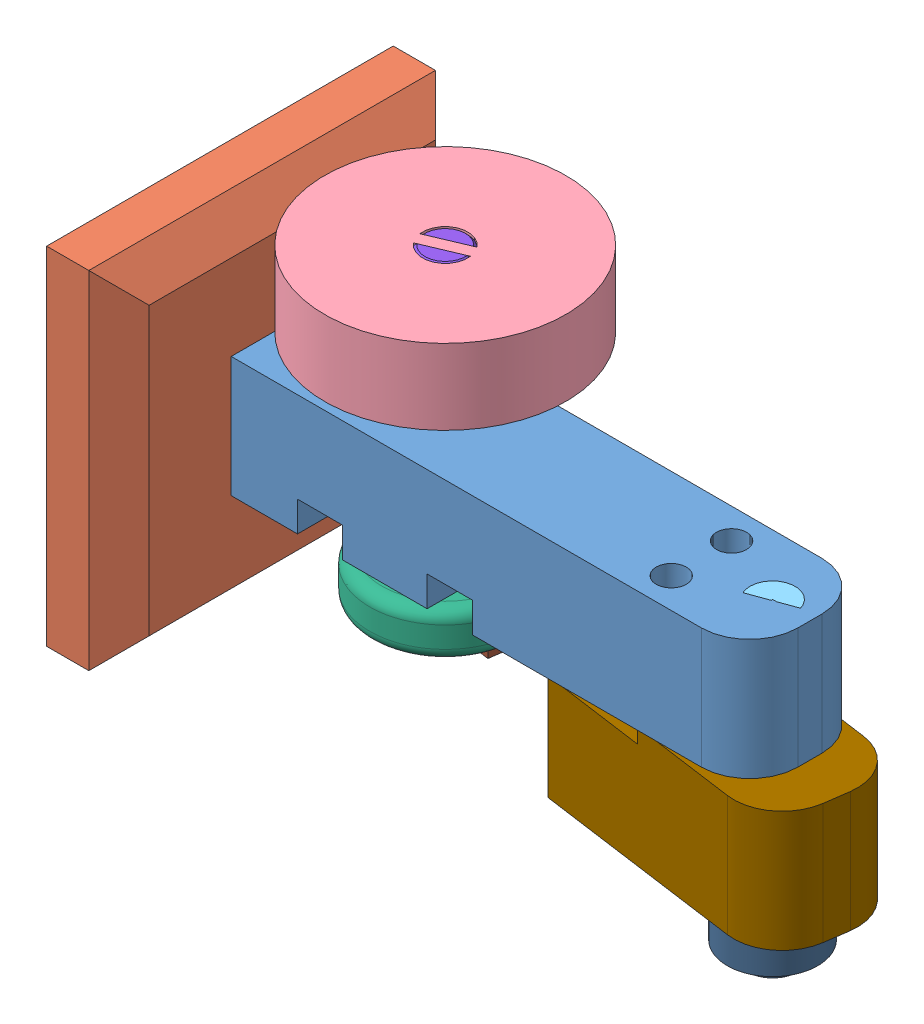
SolidWorks assembly Assem1 final project, configuration Default. Lengths in mm.
Overall size (134.06 95.45 73.03).
11 component instances, 11 part files, 22 mates.
Components (placement in the parent):
- PART7 main body-1: PART7 main body [Default] at (-9.211 -41.619 -75.801) x (0 0 -1) z (1 0 0) size (25.4 25.4 109.22)
- PART1base-1: PART1base [Default] at (-133.671 -41.0985 -75.9637) x (0 0 1) z (-1 0 0) size (73.03 73.03 15.24)
- PART11 bolt-1: PART11 bolt [Default] at (-124.146 -41.0985 -75.9637) x (0 0 -1) z (1 0 0) size (9.53 9.53 19.05)
- PART10 flywheel-1: PART10 flywheel [Default] at (-86.046 1.2562 -75.801) x (-0.388119 0 -0.921609) z (0 -1 0) size (50.8 50.8 25.4)
- PART2CONNECTING BOLT-1: PART2CONNECTING BOLT [Default] at (-17.085 -28.919 -75.801) x (0.999969 0 0.007855) z (0 1 0) size (9.53 9.53 57.15)
- PART3 SHAFT WHEEL-1: PART3 SHAFT WHEEL [Default] at (-86.046 -63.844 -75.801) x (0.990415 0 0.138122) z (0 1 0) size (32.12 31.75 9.9)
- PART4 SMALL BAR-1: PART4 SMALL BAR [Default] at (-84.7304 -54.319 -85.2347) x (0.683793 0 -0.729676) z (0 -1 0) size (4.75 4.75 19.05)
- PART5 BIG BAR-1: PART5 BIG BAR [Default] at (-86.046 1.2562 -75.801) x (-0.388119 0 -0.921609) z (0 1 0) size (9.53 9.53 65.1)
- PART6 cylinder-1: PART6 cylinder [Default] at (-1.3622 -68.797 -73.6084) x (0.138122 0 -0.990415) z (0.990415 0 0.138122) size (25.4 25.4 54.61)
- PART8 holder-1: PART8 holder [Default] at (-17.085 -87.4074 -75.801) x (0.756947 0 -0.653476) z (-0.653476 0 -0.756947) size (19.05 12.7 19.05)
- PART9 piston-1: PART9 piston [Default] at (-55.8004 -68.797 -81.2002) x (0 -1 0) z (-0.990415 0 -0.138122) size (12.7 12.7 46.61)
Mates (geometry in assembly coordinates):
- Coincident4: coincident: plane of assembly; plane of assembly; plane of PART7 main body-1 through (-118.431 -41.619 -75.801) normal (-1 0 0); plane of PART1base-1 through (-118.431 -41.0985 -75.9637) normal (1 0 0)
- Concentric4: concentric: cylinder of assembly; cylinder of assembly; cylinder of PART1base-1 through (-118.431 -41.0985 -75.9637) axis (-1 0 0) radius 3.175; cylinder of PART11 bolt-1 through (-111.446 -41.0985 -75.9637) axis (-1 0 0) radius 3.175
- Coincident8: coincident: plane of assembly; plane of assembly; plane of PART1base-1 through (-124.146 -41.0985 -75.9637) normal (-1 0 0); plane of PART11 bolt-1 through (-124.146 -41.0985 -75.9637) normal (1 0 0)
- Distance2: distance = 1.778 mm: plane of assembly; plane of assembly; plane of PART6 cylinder-1 through (-57.2029 -56.097 -68.5729) normal (0 1 0); plane of PART7 main body-1 through (-118.431 -54.319 -63.101) normal (0 -1 0)
- Concentric5: concentric: cylinder of assembly; cylinder of assembly; cylinder of PART7 main body-1 through (-17.085 -37.809 -75.801) axis (0 -1 0) radius 4.7625; cylinder of PART6 cylinder-1 through (-17.085 -56.097 -75.801) axis (0 -1 0) radius 4.7625
- Concentric6: concentric: cylinder of assembly; cylinder of assembly; cylinder of PART2CONNECTING BOLT-1 through (-17.085 -86.069 -75.801) axis (0 1 0) radius 4.7625; cylinder of PART6 cylinder-1 through (-17.085 -56.097 -75.801) axis (0 -1 0) radius 4.7625
- Coincident11: coincident: plane of assembly; plane of assembly; plane of PART7 main body-1 through (-118.431 -28.919 -63.101) normal (0 1 0); plane of PART2CONNECTING BOLT-1 through (-17.085 -28.919 -75.801) normal (0 1 0)
- Concentric15: concentric: cylinder of assembly; cylinder of assembly; cylinder of PART2CONNECTING BOLT-1 through (-17.085 -86.069 -75.801) axis (0 1 0) radius 4.7625; cylinder of PART8 holder-1 through (-17.085 -94.197 -75.801) axis (0 1 0) radius 4.7625
- Coincident20: coincident: plane of assembly; plane of assembly; plane of PART6 cylinder-1 through (-57.2029 -81.497 -68.5729) normal (0 -1 0); plane of PART8 holder-1 through (-17.085 -81.497 -75.801) normal (0 1 0)
- Concentric16: concentric: cylinder of assembly; cylinder of assembly; cylinder of PART6 cylinder-1 through (-25.5628 -68.797 -76.9833) axis (-0.990415 0 -0.138122) radius 6.35; cylinder of PART9 piston-1 through (-44.8573 -68.797 -79.6741) axis (-0.990415 0 -0.138122) radius 6.35
- Concentric17: concentric: cylinder of assembly; cylinder of assembly; cylinder of PART7 main body-1 through (-86.046 -28.919 -75.801) axis (0 -1 0) radius 4.7625; cylinder of PART3 SHAFT WHEEL-1 through (-86.046 -54.319 -75.801) axis (0 -1 0) radius 4.7625
- Coincident21: coincident: plane of assembly; plane of assembly; plane of PART7 main body-1 through (-118.431 -54.319 -63.101) normal (0 -1 0); plane of PART3 SHAFT WHEEL-1 through (-73.1129 -54.319 -82.7671) normal (0 1 0)
- Concentric18: concentric: cylinder of assembly; cylinder of assembly; cylinder of PART3 SHAFT WHEEL-1 through (-84.7304 -54.319 -85.2347) axis (0 -1 0) radius 2.3749; cylinder of PART9 piston-1 through (-84.7304 -75.147 -85.2347) axis (0 1 0) radius 2.3749
- Concentric19: concentric: cylinder of assembly; cylinder of assembly; cylinder of PART4 SMALL BAR-1 through (-84.7304 -73.369 -85.2347) axis (0 1 0) radius 2.3749; cylinder of PART9 piston-1 through (-84.7304 -75.147 -85.2347) axis (0 1 0) radius 2.3749
- Coincident22: coincident: plane of assembly; plane of assembly; plane of PART3 SHAFT WHEEL-1 through (-73.1129 -54.319 -82.7671) normal (0 1 0); plane of PART4 SMALL BAR-1 through (-84.7304 -54.319 -85.2347) normal (0 1 0)
- Concentric21: concentric: cylinder of assembly; cylinder of assembly; cylinder of PART7 main body-1 through (-86.046 -28.919 -75.801) axis (0 -1 0) radius 4.7625; cylinder of PART5 BIG BAR-1 through (-86.046 -63.844 -75.801) axis (0 1 0) radius 4.7625
- Coincident24: coincident: plane of assembly; plane of assembly; plane of PART3 SHAFT WHEEL-1 through (-73.1129 -63.844 -82.7671) normal (0 -1 0); plane of PART5 BIG BAR-1 through (-86.046 -63.844 -75.801) normal (0 -1 0)
- Concentric23: concentric: cylinder of assembly; cylinder of assembly; cylinder of PART10 flywheel-1 through (-86.046 1.2562 -75.801) axis (0 -1 0) radius 4.7625; cylinder of PART5 BIG BAR-1 through (-86.046 -63.844 -75.801) axis (0 1 0) radius 4.7625
- Parallel4: parallel: plane of assembly; plane of assembly; plane of PART10 flywheel-1 through (-82.1498 -1.9188 -78.8199) normal (-0.388119 0 -0.921609); plane of PART5 BIG BAR-1 through (-81.8921 -1.9188 -78.9284) normal (0.388119 0 0.921609)
- Coincident31: coincident: plane of assembly; plane of assembly; plane of PART10 flywheel-1 through (-86.046 1.2562 -75.801) normal (0 1 0); plane of PART5 BIG BAR-1 through (-86.046 1.2562 -75.801) normal (0 1 0)
- Coincident32: coincident: plane of assembly; circle of assembly; plane of PART3 SHAFT WHEEL-1 through (-73.1129 -63.844 -82.7671) normal (0 -1 0); circle of PART5 BIG BAR-1
- Lock2: lock: unknown of PART3 SHAFT WHEEL-1; unknown of PART5 BIG BAR-1
